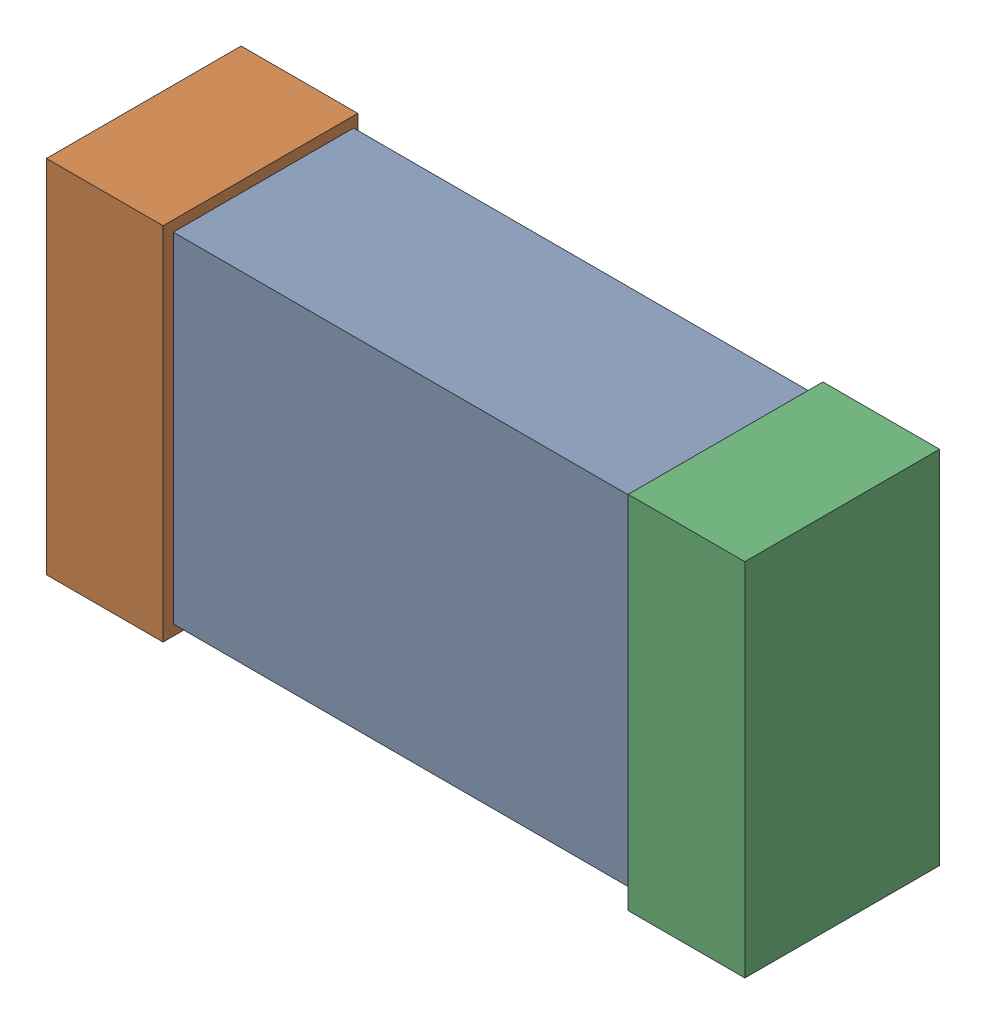
SolidWorks assembly C8, configuration Default. Lengths in mm.
Overall size (1.65 0.85 0.46).
6 component instances, 2 part files, 0 mates.
Components (placement in the parent):
- 432120720_7-1: 432120720_7 [Default] at (44.0653 17.2336 -0.8615) size (1.5 0.8 0.42)
  - Extruded (12)-1: Extruded (12) [Default] at origin size (1.5 0.8 0.42)
- 432120464_14-1: 432120464_14 [Default] at (43.3795 17.2336 -0.8715) size (0.28 0.85 0.46)
  - Extruded (11)-1: Extruded (11) [Default] at origin size (0.28 0.85 0.46)
- 432120464_15-1: 432120464_15 [Default] at (44.751 17.2336 -0.8715) size (0.28 0.85 0.46)
  - Extruded (11)-1: Extruded (11) [Default] at origin size (0.28 0.85 0.46)
